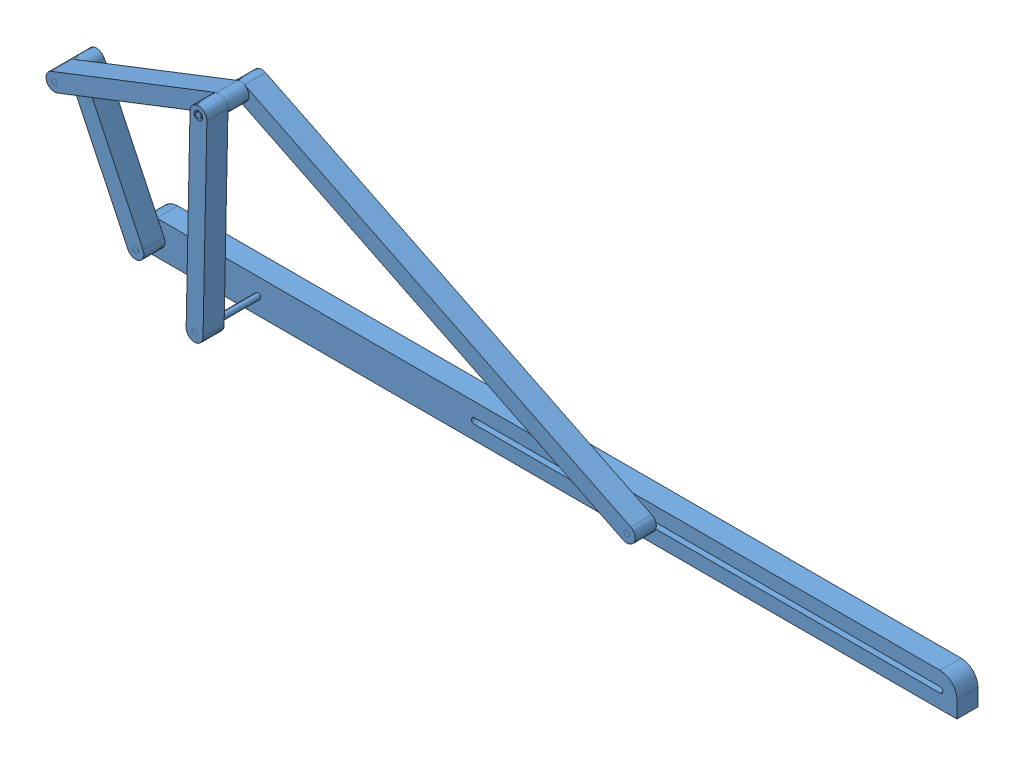
SolidWorks assembly Ensamble_Cuatro_Barras_2, configuration Default. Lengths in mm.
Overall size (216.04 51.81 20).
10 component instances, 1 part files, 17 mates.
Components (placement in the parent):
- Cuatro_Barras_2-1: Cuatro_Barras_2 [Soporte] at (-18.4727 92.1306 156.1691) size (193.7 8 5)
- Cuatro_Barras_2-2: Cuatro_Barras_2 [Eslabon A] at (-18.4727 92.1306 156.1691) x (0.56584 0.824515 0) z (0 0 1) size (20.5 32.58 5)
- Cuatro_Barras_2-3: Cuatro_Barras_2 [Eslabon B] at (-37.9704 89.3297 161.1691) x (0.934763 0.355271 0) z (0 0 1) size (46 4.31 5)
- Cuatro_Barras_2-4: Cuatro_Barras_2 [Eslabon C] at (-10.2555 74.0501 166.1691) x (0.657613 0.753356 0) z (0 0 1) size (38.5 32.89 5)
- Cuatro_Barras_2-5: Cuatro_Barras_2 [Eslabon E] at (-56.0894 118.5165 156.1691) x (0.985651 -0.168793 0) z (0 0 1) size (101.82 32.89 5)
- Cuatro_Barras_2-7: Cuatro_Barras_2 [PIN2] at (9.5299 109.5907 156.1691) x (-0.88249 0.470331 0) z (0 0 1) size (1.33 1.33 10)
- Cuatro_Barras_2-11: Cuatro_Barras_2 [PIN] at (-150.7937 92.1306 161.1691) size (1.33 1.33 20)
- Cuatro_Barras_2-12: Cuatro_Barras_2 [PIN2] at (-49.2001 93.3273 161.1691) size (1.33 1.33 10)
- Cuatro_Barras_2-13: Cuatro_Barras_2 [PIN3] at (-52.0517 108.2277 161.1691) size (1.33 1.33 15)
- Cuatro_Barras_2-14: Cuatro_Barras_2 [PIN2] at (130.956 93.5978 156.1691) x (-0.538011 0.842938 0) z (0 0 1) size (1.33 1.33 10)
Mates (geometry in assembly coordinates):
- Coincidente1: coincident anti-aligned: plane of Cuatro_Barras_2-1 through (-18.4727 92.1306 156.1691) normal (0 0 1); plane of Cuatro_Barras_2-2 through (-18.4727 92.1306 156.1691) normal (0 0 -1)
- Concéntrica1: concentric aligned: circle of Cuatro_Barras_2-1; circle of Cuatro_Barras_2-2
- Concéntrica2: concentric aligned: circle of Cuatro_Barras_2-1; circle of Cuatro_Barras_2-4
- Concéntrica3: concentric aligned: circle of Cuatro_Barras_2-2; circle of Cuatro_Barras_2-3
- Concéntrica4: concentric aligned: circle of Cuatro_Barras_2-3; circle of Cuatro_Barras_2-4
- Concéntrica5: concentric aligned: circle of Cuatro_Barras_2-3; circle of Cuatro_Barras_2-5
- Concéntrica6: concentric aligned: circle of Cuatro_Barras_2-2; circle of Cuatro_Barras_2-7
- Coincidente8: coincident aligned: plane of Cuatro_Barras_2-2 through (-18.4727 92.1306 161.1691) normal (0 0 1); circle of Cuatro_Barras_2-7
- Coincidente12: coincident anti-aligned: plane of Cuatro_Barras_2-3 through (-31.9154 122.2685 166.1691) normal (0 0 1); plane of Cuatro_Barras_2-4 through (5.5273 92.1306 166.1691) normal (0 0 -1)
- Coincidente13: coincident anti-aligned: plane of Cuatro_Barras_2-3 through (-31.9154 122.2685 161.1691) normal (0 0 -1); plane of Cuatro_Barras_2-5 through (7.3816 137.0924 161.1691) normal (0 0 1)
- Coincidente14: coincident anti-aligned: plane of Cuatro_Barras_2-2 through (-18.4727 92.1306 161.1691) normal (0 0 1); plane of Cuatro_Barras_2-3 through (-31.9154 122.2685 161.1691) normal (0 0 -1)
- Coincidente15: coincident aligned: circle of Cuatro_Barras_2-4; circle of Cuatro_Barras_2-11
- Coincidente16: coincident aligned: circle of Cuatro_Barras_2-3; circle of Cuatro_Barras_2-12
- Coincidente17: coincident aligned: circle of Cuatro_Barras_2-5; circle of Cuatro_Barras_2-14
- Tangente2: tangent anti-aligned: plane of Cuatro_Barras_2-1 through (56.8273 91.4656 151.1691) normal (0 1 0); cylinder of Cuatro_Barras_2-14 through (98.9373 92.1306 151.1691) axis (0 0 1) radius 0.665
- Concéntrica9: concentric: circle of Cuatro_Barras_2-4; circle of Cuatro_Barras_2-13
- Coincidente18: coincident aligned: plane of Cuatro_Barras_2-4 through (5.5273 92.1306 171.1691) normal (0 0 1); plane of Cuatro_Barras_2-13 through (6.4471 137.1212 171.1691) normal (0 0 1)
